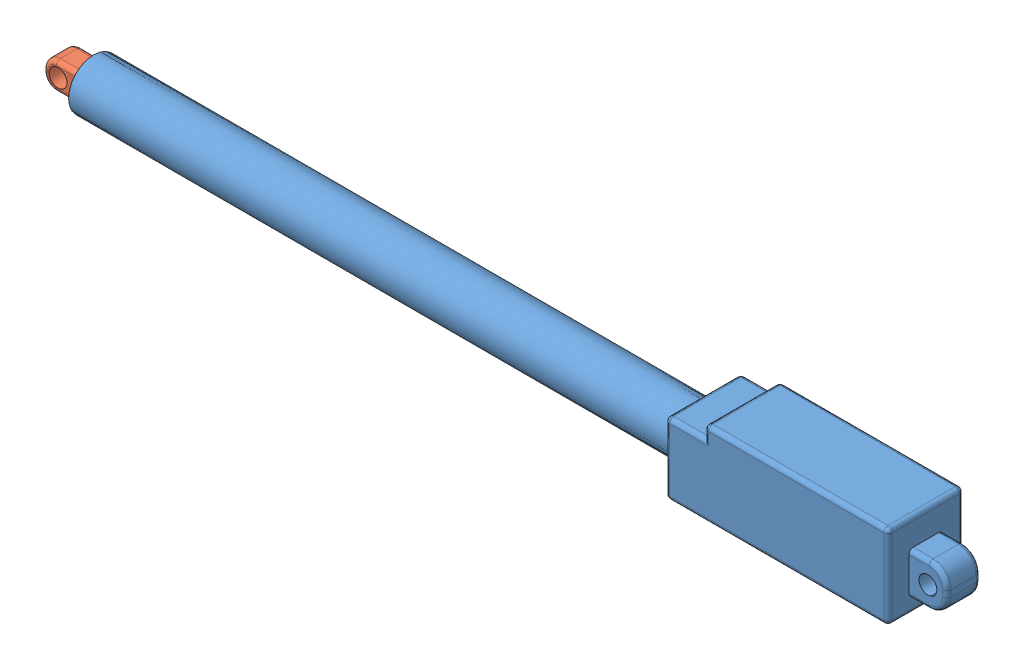
SolidWorks assembly LinAct, configuration Default. Lengths in mm.
Overall size (215.95 20 18).
2 component instances, 2 part files, 3 mates.
Components (placement in the parent):
- LinAct_Base-1: LinAct_Base [Default] at origin size (207 20 18)
- Pistion-1: Pistion [Default] at (-4.955 8.5 9) x (0 1 0) z (-1 0 0) size (9 9 149)
Mates (geometry in assembly coordinates):
- Concentric1: concentric aligned: cylinder of LinAct_Base-1 through (-145 8.5 9) axis (1 0 0) radius 6; cylinder of Pistion-1 through (-144.955 8.5 9) axis (1 0 0) radius 4.5
- Parallel1: parallel anti-aligned: plane of LinAct_Base-1 through (57.75 7.75 13) normal (0 0 1); plane of Pistion-1 through (-150.955 8.7554 6) normal (0 0 -1)
- LimitDistance2: limit distance = 208 mm: line of LinAct_Base-1 through (57.5 8.5 5) axis (0 0 1); line of Pistion-1 through (-150.5 8.5 12) axis (0 0 -1)
